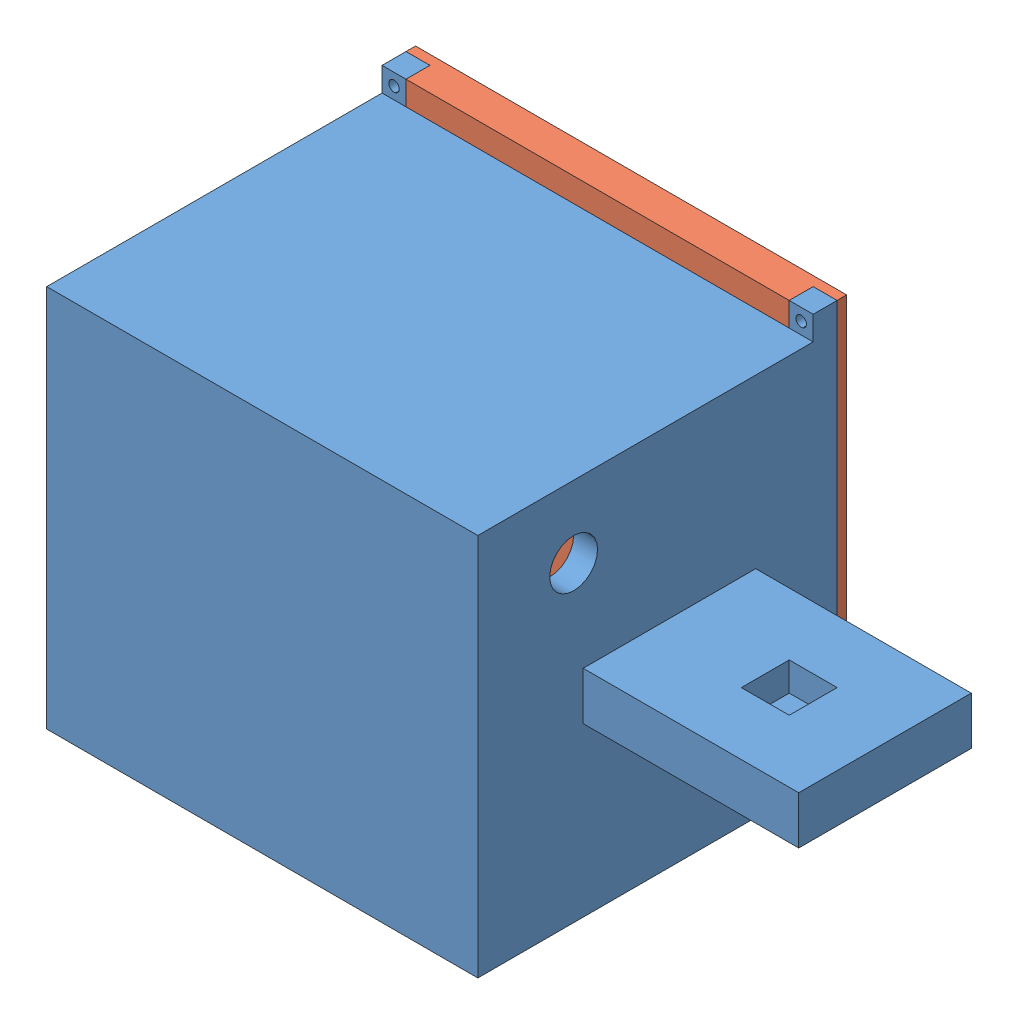
SolidWorks assembly 組合件_3, configuration 預設. Lengths in mm.
Overall size (146.5 90 77).
2 component instances, 2 part files, 5 mates.
Components (placement in the parent):
- 7_20fishbody_vertical_3-1: 7_20fishbody_vertical_3 [預設] at (1.2385 -6.4961 109.0018) size (146.5 90 75)
- fish_lid_vertical3-1: fish_lid_vertical3 [預設] at (9.8163 1.1124 104.0018) size (90 90 7)
Mates (geometry in assembly coordinates):
- 同軸心1: concentric: cylinder of 7_20fishbody_vertical_3-1 through (13.2296 -43.4062 114.0018) axis (0 0 -1) radius 1.1; cylinder of fish_lid_vertical3-1 through (13.2296 -43.4062 146.0018) axis (0 0 -1) radius 1.1
- 同軸心2: concentric: cylinder of 7_20fishbody_vertical_3-1 through (-71.7704 -43.4062 114.0018) axis (0 0 -1) radius 1.1; cylinder of fish_lid_vertical3-1 through (-71.7704 -43.4062 146.0018) axis (0 0 -1) radius 1.1
- 同軸心3: concentric: cylinder of 7_20fishbody_vertical_3-1 through (-71.7704 41.5938 114.0018) axis (0 0 -1) radius 1.1; cylinder of fish_lid_vertical3-1 through (-71.7704 41.5938 146.0018) axis (0 0 -1) radius 1.1
- 同軸心4: concentric: cylinder of 7_20fishbody_vertical_3-1 through (13.2296 41.5938 114.0018) axis (0 0 -1) radius 1.1; cylinder of fish_lid_vertical3-1 through (13.2296 41.5938 146.0018) axis (0 0 -1) radius 1.1
- 重合/共線/共點2: coincident: plane of 7_20fishbody_vertical_3-1 through (1.2385 -6.4961 109.0018) normal (0 0 -1); plane of fish_lid_vertical3-1 through (9.8163 1.1124 109.0018) normal (0 0 1)
